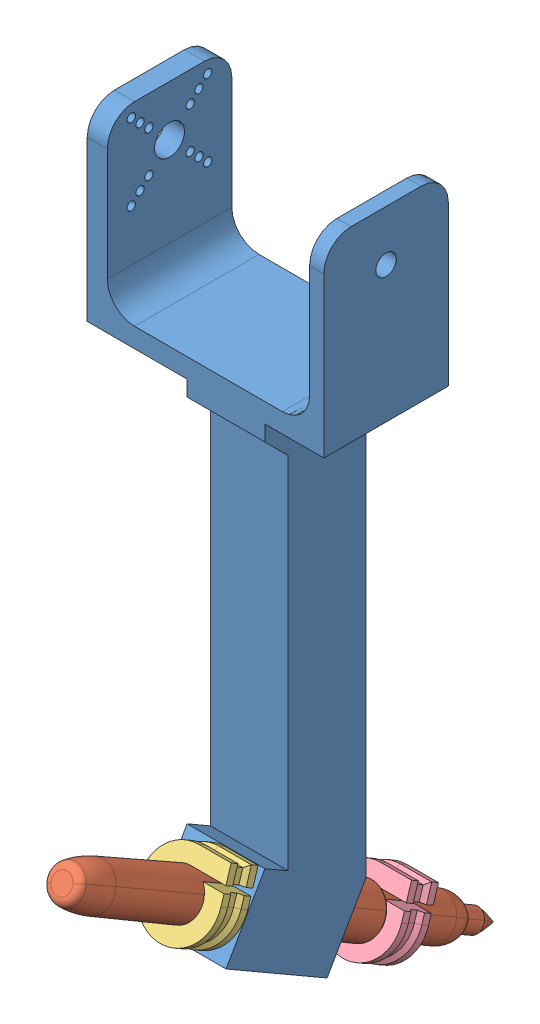
SolidWorks assembly J3, configuration Default. Lengths in mm.
Overall size (60.8 205.12 118.78).
4 component instances, 4 part files, 8 mates.
Components (placement in the parent):
- Joint 3-1: Joint 3 [Default] at origin size (60.8 179.32 41.98)
- Sharpie Marker-1: Sharpie Marker [Default] at (0 -88.7103 58.1333) x (-0.394129 0.795925 -0.459528) z (-0.919055 -0.341325 0.197064) size (12.29 127.84 12.29)
- SharpieClampLarge-1: SharpieClampLarge [Default] at (0 -110.1603 20.9808) x (1 0 0) z (0 -0.866025 0.5) size (19.8 8 19.8)
- SharpieClampSmall-1: SharpieClampSmall [Default] at (0 -137.1603 -25.7846) x (1 0 0) z (0 -0.866025 0.5) size (19.2 8 19.2)
Mates (geometry in assembly coordinates):
- Concentric1: concentric aligned: cylinder of Joint 3-1 through (0 -113.1603 15.7846) axis (0 0.5 0.866025) radius 6.25; cone of Sharpie Marker-1 through (0 -87.68 59.9176) axis (0 0.5 0.866025)
- Concentric2: concentric anti-aligned: cone of Sharpie Marker-1 through (0 -87.68 59.9176) axis (0 0.5 0.866025); cylinder of SharpieClampLarge-1 through (0 -103.13 33.1575) axis (0 -0.5 -0.866025) radius 5.7
- Distance1: distance = 46 mm aligned: plane of Sharpie Marker-1 through (0 -133.1603 -18.8564) normal (0 -0.5 -0.866025); plane of SharpieClampLarge-1 through (0 -110.1603 20.9808) normal (0 -0.5 -0.866025)
- Parallel1: parallel aligned: plane of Joint 3-1 through (-58.3656 -116.5 -10) normal (0 0.866025 -0.5); plane of SharpieClampLarge-1 through (0 -93.5564 29.9395) normal (0 0.866025 -0.5)
- Concentric3: concentric anti-aligned: cylinder of Sharpie Marker-1 through (0 -127.38 -8.8448) axis (0 0.5 0.866025) radius 5.35; cylinder of SharpieClampSmall-1 through (0 -130.13 -13.6079) axis (0 -0.5 -0.866025) radius 5.4
- Parallel2: parallel aligned: plane of Joint 3-1 through (-58.3656 -116.5 -10) normal (0 0.866025 -0.5); plane of SharpieClampSmall-1 through (0 -120.8162 -16.6759) normal (0 0.866025 -0.5)
- Coincident4: coincident anti-aligned: plane of Sharpie Marker-1 through (0 -127.63 -9.2778) normal (0 -0.5 -0.866025); plane of SharpieClampSmall-1 through (0 -127.63 -9.2778) normal (0 0.5 0.866025)
- Coincident5: coincident aligned: plane of Joint 3-1 through (-58.3656 -101.5 15.9808) normal (0 0.5 0.866025); circle of SharpieClampLarge-1
